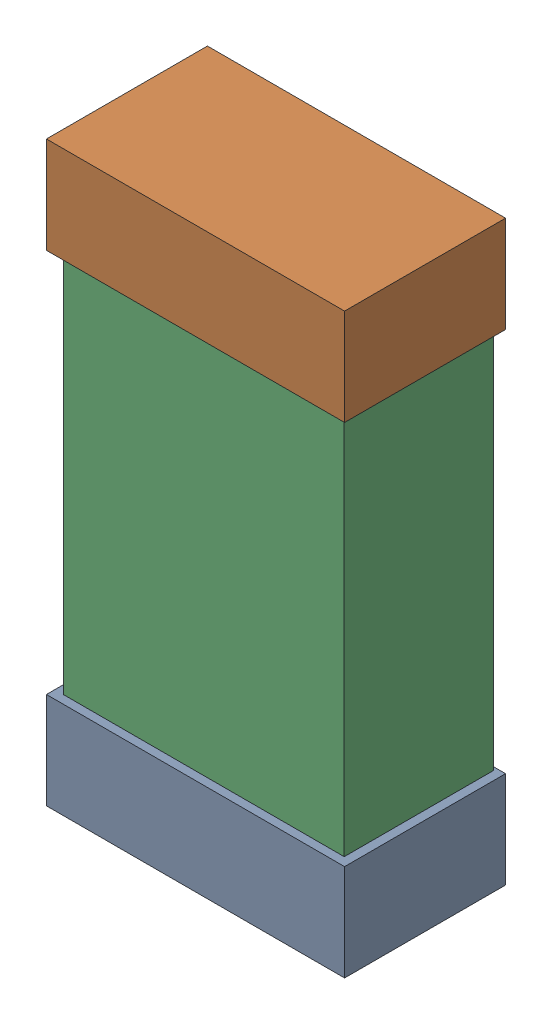
SolidWorks assembly C34, configuration Default. Lengths in mm.
Overall size (0.85 1.65 0.46).
6 component instances, 2 part files, 0 mates.
Components (placement in the parent):
- 432138512_54-1: 432138512_54 [Default] at (21.2403 57.8813 -0.8715) size (0.85 0.28 0.46)
  - Extruded-1: Extruded [Default] at origin size (0.85 0.28 0.46)
- 432138512_55-1: 432138512_55 [Default] at (21.2403 59.2528 -0.8715) size (0.85 0.28 0.46)
  - Extruded-1: Extruded [Default] at origin size (0.85 0.28 0.46)
- 432124816_27-1: 432124816_27 [Default] at (21.2403 58.567 -0.8615) size (0.8 1.5 0.42)
  - Extruded (1)-1: Extruded (1) [Default] at origin size (0.8 1.5 0.42)
